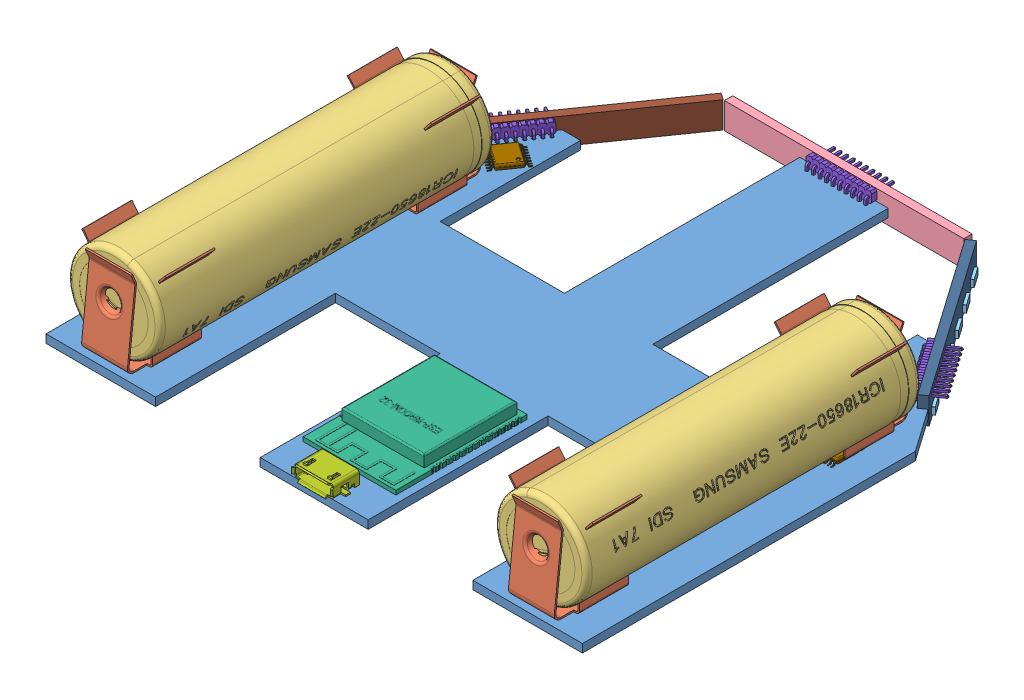
SolidWorks assembly SkateLight_Electrical, configuration Default. Lengths in mm.
Overall size (105.77 23.47 107.47).
45 component instances, 11 part files, 37 mates.
Components (placement in the parent):
- MainPCB-1: MainPCB [Default] at (0 18.0296 0) x (1 0 0) z (0 1 0) size (104.14 102.87 1.6)
- Battery_clip_36-54-ND -1: Battery_clip_36-54-ND  [Default] at (-10.6363 28.7736 -14.0353) size (16.51 19.53 13.31)
- Battery_clip_36-54-ND -2: Battery_clip_36-54-ND  [Default] at (-10.6363 28.7736 -56.0447) x (-1 0 0) z (0 0 -1) size (16.51 19.53 13.31)
- Battery Samsung ICR 18650 -22E-1: Battery Samsung ICR 18650 -22E [Default] at (-4.1947 39.4453 -65.3584) x (0 0 1) z (-0.327593 0.944819 0) size (65 18 18)
  - Battery Samsung ICR 18650 -22E.stp-1: Battery Samsung ICR 18650 -22E.stp [Default] at origin size (65 18 18)
    - Samsung_ICR18650-22E.stp-1: Samsung_ICR18650-22E.stp [Default] at (-2.1716 -9.5821 -7.9726) x (0 0 -1) z (1 0 0) size (18 18 65)
- PCB_FRO-1: PCB_FRO [Default] at (-64.2042 18.3628 -97.9034) x (-1 0 0) z (0 0 -1) size (46.48 5.08 2.12)
  - LEDPanel-1: LEDPanel [Default] at (-12.1342 0.9368 4.9666) size (46.48 5.08 1.6)
  - 1206_5000k_LUMINUS_MP3014_1100-1: 1206_5000k_LUMINUS_MP3014_1100 [Default] at (-32.6511 -0.3332 6.5666) x (0 1 0) z (1 0 0) size (1.4 0.52 3)
  - 1206_5000k_LUMINUS_MP3014_1100-2: 1206_5000k_LUMINUS_MP3014_1100 [Default] at (-26.9361 -0.3332 6.5666) x (0 1 0) z (1 0 0) size (1.4 0.52 3)
  - 1206_5000k_LUMINUS_MP3014_1100-3: 1206_5000k_LUMINUS_MP3014_1100 [Default] at (-21.2211 -0.3332 6.5666) x (0 1 0) z (1 0 0) size (1.4 0.52 3)
  - 1206_5000k_LUMINUS_MP3014_1100-4: 1206_5000k_LUMINUS_MP3014_1100 [Default] at (-15.5061 -0.3332 6.5666) x (0 1 0) z (1 0 0) size (1.4 0.52 3)
  - 1206_5000k_LUMINUS_MP3014_1100-5: 1206_5000k_LUMINUS_MP3014_1100 [Default] at (-9.7911 -0.3332 6.5666) x (0 1 0) z (1 0 0) size (1.4 0.52 3)
  - 1206_5000k_LUMINUS_MP3014_1100-6: 1206_5000k_LUMINUS_MP3014_1100 [Default] at (-4.0761 -0.3332 6.5666) x (0 1 0) z (1 0 0) size (1.4 0.52 3)
  - 1206_5000k_LUMINUS_MP3014_1100-7: 1206_5000k_LUMINUS_MP3014_1100 [Default] at (1.6389 -0.3332 6.5666) x (0 1 0) z (1 0 0) size (1.4 0.52 3)
  - 1206_5000k_LUMINUS_MP3014_1100-8: 1206_5000k_LUMINUS_MP3014_1100 [Default] at (7.3539 -0.3332 6.5666) x (0 1 0) z (1 0 0) size (1.4 0.52 3)
- ESP-WROOM-32-1: ESP-WROOM-32 [Default] at (-52.07 19.5946 -19.6055) x (1 0 0) z (0 1 0) size (18.07 25.54 3.04)
- Hirose Micro USB Digikey PN H11635CT-ND-1: Hirose Micro USB Digikey PN H11635CT-ND [Default] at (-52.07 20.8996 0.6) size (8.8 3 5.6)
- Connx10_M50-3931042-1: Connx10_M50-3931042 [Default] at (-46.355 20.6796 -101.37) x (0 -1 0) z (-1 0 0) size (4.5 5.7 12.7)
- Connx10_M50-3931042-2: Connx10_M50-3931042 [Default] at (-9.4179 20.6796 -72.8932) x (0 -1 0) z (-0.573576 0 -0.819152) size (4.5 5.7 12.7)
- Connx10_M50-3931042-3: Connx10_M50-3931042 [Default] at (-88.1661 20.6796 -82.2561) x (0 -1 0) z (-0.573576 0 0.819152) size (4.5 5.7 12.7)
- TSSOP16_STP08DP05-1: TSSOP16_STP08DP05 [Default] at (-15.3711 19.5197 -74.1303) x (0.819152 0 -0.573576) z (0 1 0) size (5.11 6.43 1.1)
- Battery Samsung ICR 18650 -22E-2: Battery Samsung ICR 18650 -22E [Default] at (-81.8386 33.1672 -65.3584) x (0 0 1) z (0.327593 0.944819 0) size (65 18 18)
  - Battery Samsung ICR 18650 -22E.stp-1: Battery Samsung ICR 18650 -22E.stp [Default] at origin size (65 18 18)
    - Samsung_ICR18650-22E.stp-1: Samsung_ICR18650-22E.stp [Default] at (-2.1716 -9.5821 -7.9726) x (0 0 -1) z (1 0 0) size (18 18 65)
- Battery_clip_36-54-ND -3: Battery_clip_36-54-ND  [Default] at (-93.5038 28.7736 -14.0353) size (16.51 19.53 13.31)
- Battery_clip_36-54-ND -4: Battery_clip_36-54-ND  [Default] at (-93.5038 28.7736 -56.0447) x (-1 0 0) z (0 0 -1) size (16.51 19.53 13.31)
- TSSOP16_STP08DP05-2: TSSOP16_STP08DP05 [Default] at (-7.7532 19.5197 -56.9271) x (1 0 0) z (0 1 0) size (5.11 6.43 1.1)
- TSSOP16_STP08DP05-3: TSSOP16_STP08DP05 [Default] at (-88.7689 19.5197 -74.1303) x (-0.819152 0 -0.573576) z (0 1 0) size (5.11 6.43 1.1)
- PCB_SIDE_LED_R-1: PCB_SIDE_LED_R [Default] at (-28.8693 18.3628 -94.6289) x (-0.573576 0 -0.819152) z (0.819152 0 -0.573576) size (37.46 5.08 2.12)
  - LEDPanel2R-1: LEDPanel2R [Default] at (-12.1342 0.9368 4.9666) size (37.46 5.08 1.6)
  - 1206_5000k_LUMINUS_MP3014_1100-1: 1206_5000k_LUMINUS_MP3014_1100 [Default] at (-27.5267 -0.3332 6.5666) x (0 1 0) z (1 0 0) size (1.4 0.52 3)
  - 1206_5000k_LUMINUS_MP3014_1100-2: 1206_5000k_LUMINUS_MP3014_1100 [Default] at (-21.3698 -0.3332 6.5666) x (0 1 0) z (1 0 0) size (1.4 0.52 3)
  - 1206_5000k_LUMINUS_MP3014_1100-3: 1206_5000k_LUMINUS_MP3014_1100 [Default] at (-15.2128 -0.3332 6.5666) x (0 1 0) z (1 0 0) size (1.4 0.52 3)
  - 1206_5000k_LUMINUS_MP3014_1100-4: 1206_5000k_LUMINUS_MP3014_1100 [Default] at (-9.0558 -0.3332 6.5666) x (0 1 0) z (1 0 0) size (1.4 0.52 3)
  - 1206_5000k_LUMINUS_MP3014_1100-5: 1206_5000k_LUMINUS_MP3014_1100 [Default] at (-2.8989 -0.3332 6.5666) x (0 1 0) z (1 0 0) size (1.4 0.52 3)
  - 1206_5000k_LUMINUS_MP3014_1100-9: 1206_5000k_LUMINUS_MP3014_1100 [Default] at (3.2581 -0.3332 6.5666) x (0 1 0) z (1 0 0) size (1.4 0.52 3)
- PCB_SIDE_LED_L-3: PCB_SIDE_LED_L [Default] at (-89.1905 18.3628 -74.7494) x (-0.573576 0 0.819152) z (-0.819152 0 -0.573576) size (37.46 5.08 2.12)
  - LEDPanel2L-1: LEDPanel2L [Default] at (-12.1342 0.9368 4.9666) size (37.46 5.08 1.6)
  - 1206_5000k_LUMINUS_MP3014_1100-1: 1206_5000k_LUMINUS_MP3014_1100 [Default] at (-27.5267 -0.3332 6.5666) x (0 1 0) z (1 0 0) size (1.4 0.52 3)
  - 1206_5000k_LUMINUS_MP3014_1100-2: 1206_5000k_LUMINUS_MP3014_1100 [Default] at (-21.3698 -0.3332 6.5666) x (0 1 0) z (1 0 0) size (1.4 0.52 3)
  - 1206_5000k_LUMINUS_MP3014_1100-3: 1206_5000k_LUMINUS_MP3014_1100 [Default] at (-15.2128 -0.3332 6.5666) x (0 1 0) z (1 0 0) size (1.4 0.52 3)
  - 1206_5000k_LUMINUS_MP3014_1100-4: 1206_5000k_LUMINUS_MP3014_1100 [Default] at (-9.0558 -0.3332 6.5666) x (0 1 0) z (1 0 0) size (1.4 0.52 3)
  - 1206_5000k_LUMINUS_MP3014_1100-5: 1206_5000k_LUMINUS_MP3014_1100 [Default] at (-2.8989 -0.3332 6.5666) x (0 1 0) z (1 0 0) size (1.4 0.52 3)
  - 1206_5000k_LUMINUS_MP3014_1100-9: 1206_5000k_LUMINUS_MP3014_1100 [Default] at (3.2581 -0.3332 6.5666) x (0 1 0) z (1 0 0) size (1.4 0.52 3)
Mates (geometry in assembly coordinates):
- Coincident7: coincident: plane of MainPCB-1 through (0 19.6296 -102.87) normal (0 0 -1); plane of PCB_FRO-1/LEDPanel-1 through (-52.07 19.2996 -102.87) normal (0 0 1)
- Coincident28: coincident: plane of MainPCB-1 through (0 19.6296 0) normal (0 1 0); plane of Connx10_M50-3931042-1 through (-57.785 19.6296 -101.87) normal (0 -1 0)
- Coincident29: coincident: plane of MainPCB-1 through (-52.07 18.0296 0) normal (-1 0 0); plane of Connx10_M50-3931042-1 through (-52.07 20.6796 -101.37) normal (1 0 0)
- Coincident33: coincident: plane of MainPCB-1 through (0 19.6296 0) normal (0 1 0); plane of Connx10_M50-3931042-2 through (-15.5643 19.6296 -82.5429) normal (0 -1 0)
- Coincident36: coincident: plane of MainPCB-1 through (0 19.6296 0) normal (0 1 0); plane of Connx10_M50-3931042-3 through (-90.761 19.6296 -79.422) normal (0 -1 0)
- Concentric1: concentric: cylinder of Battery_clip_36-54-ND -1 through (-10.6363 28.7736 -4.5103) axis (0 0 -1) radius 7.9502; cylinder of Battery_clip_36-54-ND -2 through (-10.6363 28.7736 -65.5697) axis (0 0 1) radius 7.9502
- Distance1: distance = 63 mm: sphere of Battery_clip_36-54-ND -2; sphere of Battery_clip_36-54-ND -1
- Concentric3: concentric: cylinder of Battery_clip_36-54-ND -1 through (-10.6363 28.7736 -4.5103) axis (0 0 -1) radius 7.9502; cylinder of Battery Samsung ICR 18650 -22E-1/Battery Samsung ICR 18650 -22E.stp-1/Samsung_ICR18650-22E.stp-1 through (-10.6363 28.7736 -67.53) axis (0 0 1) radius 9
- Distance3: distance = 1 mm: plane of Battery Samsung ICR 18650 -22E-1/Battery Samsung ICR 18650 -22E.stp-1/Samsung_ICR18650-22E.stp-1 through (-10.6363 28.7736 -2.54) normal (0 0 1); sphere of Battery_clip_36-54-ND -1
- Coincident15: coincident: line of PCB_FRO-1/LEDPanel-1 through (-75.311 16.7596 -104.47) axis (0 0 1); plane of PCB_SIDE_LED_L-3/LEDPanel2L-1 through (-76.8651 16.7596 -103.8004) normal (0 -1 0)
- Coincident27: coincident: plane of PCB_FRO-1/LEDPanel-1 through (-52.07 19.2996 -102.87) normal (0 0 1); plane of Connx10_M50-3931042-1 through (-46.355 20.6796 -102.87) normal (0 0 -1)
- Distance14: distance = 1.27 mm: plane of PCB_SIDE_LED_L-3/LEDPanel2L-1 through (-98.3542 16.7596 -73.1108) normal (-0.573576 0 0.819152); plane of Connx10_M50-3931042-3 through (-95.4959 20.6796 -72.6599) normal (-0.573576 0 0.819152)
- Coincident37: coincident: plane of MainPCB-1 through (0 19.6296 0) normal (0 1 0); plane of TSSOP16_STP08DP05-1 through (-18.4862 19.6296 -74.4228) normal (0 -1 0)
- Coincident38: coincident: plane of MainPCB-1 through (0 19.6296 0) normal (0 1 0); plane of TSSOP16_STP08DP05-2 through (-10.1371 19.6296 -58.9535) normal (0 -1 0)
- Coincident39: coincident: plane of MainPCB-1 through (0 19.6296 0) normal (0 1 0); plane of ESP-WROOM-32-1 through (-43.07 19.6296 -32.3555) normal (0 -1 0)
- Coincident40: coincident: plane of ESP-WROOM-32-1 through (-52.07 19.5946 -19.6055) normal (1 0 0); plane of assembly through (-52.07 0 0) normal (1 0 0)
- Coincident42: coincident: plane of MainPCB-1 through (0 19.6296 0) normal (0 1 0); plane of Hirose Micro USB Digikey PN H11635CT-ND-1 through (-56.47 19.6296 -2.6) normal (0 -1 0)
- Coincident43: coincident: plane of Hirose Micro USB Digikey PN H11635CT-ND-1 through (-52.07 20.8996 0.6) normal (1 0 0); plane of assembly through (-52.07 0 0) normal (1 0 0)
- Coincident44: coincident: plane of MainPCB-1 through (0 19.6296 0) normal (0 0 1); plane of Hirose Micro USB Digikey PN H11635CT-ND-1 through (-52.07 20.8996 0) normal (0 0 1)
- Lock1: lock: unknown of MainPCB-1
- Coincident48: coincident: plane of MainPCB-1 through (0 19.6296 0) normal (0 1 0); plane of Battery_clip_36-54-ND -1 through (-15.5639 19.6296 -4.5103) normal (0 -1 0)
- Parallel2: parallel: plane of MainPCB-1 through (0 19.6296 0) normal (0 0 1); plane of Battery_clip_36-54-ND -3 through (-93.5038 28.7736 -12.4097) normal (0 0 -1)
- Coincident50: coincident: plane of MainPCB-1 through (0 19.6296 0) normal (0 1 0); plane of Battery_clip_36-54-ND -4 through (-88.5762 19.6296 -65.5697) normal (0 -1 0)
- Distance15: distance = 0.127 mm: plane of MainPCB-1 through (1.9205 19.6296 -2.7427) normal (0.573576 0 -0.819152); plane of PCB_SIDE_LED_L-3/LEDPanel2L-1 through (-98.3542 16.7596 -73.1108) normal (-0.573576 0 0.819152)
- Distance16: distance = 1.27 mm: plane of PCB_SIDE_LED_L-3/LEDPanel2L-1 through (-76.8651 16.7596 -103.8004) normal (0 -1 0); plane of MainPCB-1 through (0 18.0296 0) normal (0 -1 0)
- Coincident52: coincident: plane of PCB_FRO-1/LEDPanel-1 through (-28.829 16.7596 -104.47) normal (0 -1 0); plane of PCB_SIDE_LED_L-3/LEDPanel2L-1 through (-76.8651 16.7596 -103.8004) normal (0 -1 0)
- Coincident53: coincident: plane of PCB_FRO-1/LEDPanel-1 through (-52.07 19.2996 -102.87) normal (-1 0 0); plane of assembly through (-52.07 0 0) normal (1 0 0)
- Coincident54: coincident: plane of Battery_clip_36-54-ND -3 through (-93.5038 28.7736 -14.0353) normal (1 0 0); plane of assembly through (-93.5038 0 0) normal (1 0 0)
- Distance17: distance = 2.54 mm: plane of Battery Samsung ICR 18650 -22E-2/Battery Samsung ICR 18650 -22E.stp-1/Samsung_ICR18650-22E.stp-1 through (-93.5038 28.7736 -2.54) normal (0 0 1); plane of MainPCB-1 through (0 19.6296 0) normal (0 0 1)
- Distance18: distance = 0.127 mm: plane of MainPCB-1 through (-98.9328 19.6296 -69.2735) normal (-0.819152 0 -0.573576); plane of PCB_SIDE_LED_L-3/LEDPanel2L-1 through (-86.299 19.2996 -87.5379) normal (0.819152 0 0.573576)
- Distance19: distance = 0.127 mm: plane of MainPCB-1 through (1.9205 19.6296 -2.7427) normal (0.573576 0 -0.819152); plane of PCB_SIDE_LED_L-3/LEDPanel2L-1 through (-98.3542 16.7596 -73.1108) normal (-0.573576 0 0.819152)
- Coincident57: coincident: plane of PCB_FRO-1/LEDPanel-1 through (-28.829 16.7596 -104.47) normal (0 -1 0); plane of PCB_SIDE_LED_L-3/LEDPanel2L-1 through (-76.8651 16.7596 -103.8004) normal (0 -1 0)
- Distance20: distance = 1.27 mm: plane of PCB_FRO-1/LEDPanel-1 through (-28.829 16.7596 -104.47) normal (0 -1 0); plane of MainPCB-1 through (0 18.0296 0) normal (0 -1 0)
- Distance21: distance = 0.127 mm: plane of MainPCB-1 through (29.0538 19.6296 -20.3437) normal (0.819152 0 -0.573576); plane of PCB_SIDE_LED_R-1/LEDPanel2R-1 through (-17.841 19.2996 -87.5379) normal (-0.819152 0 0.573576)
- Distance22: distance = 0.127 mm: plane of PCB_SIDE_LED_R-1/LEDPanel2R-1 through (-5.7858 16.7596 -73.1108) normal (0.573576 0 0.819152); plane of MainPCB-1 through (-36.1815 19.6296 -51.6725) normal (-0.573576 0 -0.819152)
- Coincident61: coincident: plane of PCB_FRO-1/LEDPanel-1 through (-28.829 16.7596 -104.47) normal (0 -1 0); plane of PCB_SIDE_LED_R-1/LEDPanel2R-1 through (-5.7858 16.7596 -73.1108) normal (0 -1 0)
- Parallel3: parallel: plane of TSSOP16_STP08DP05-1 through (-15.7225 19.447 -78.7905) normal (0.819152 0 -0.573576); plane of PCB_SIDE_LED_R-1/LEDPanel2R-1 through (-17.841 19.2996 -87.5379) normal (-0.819152 0 0.573576)
